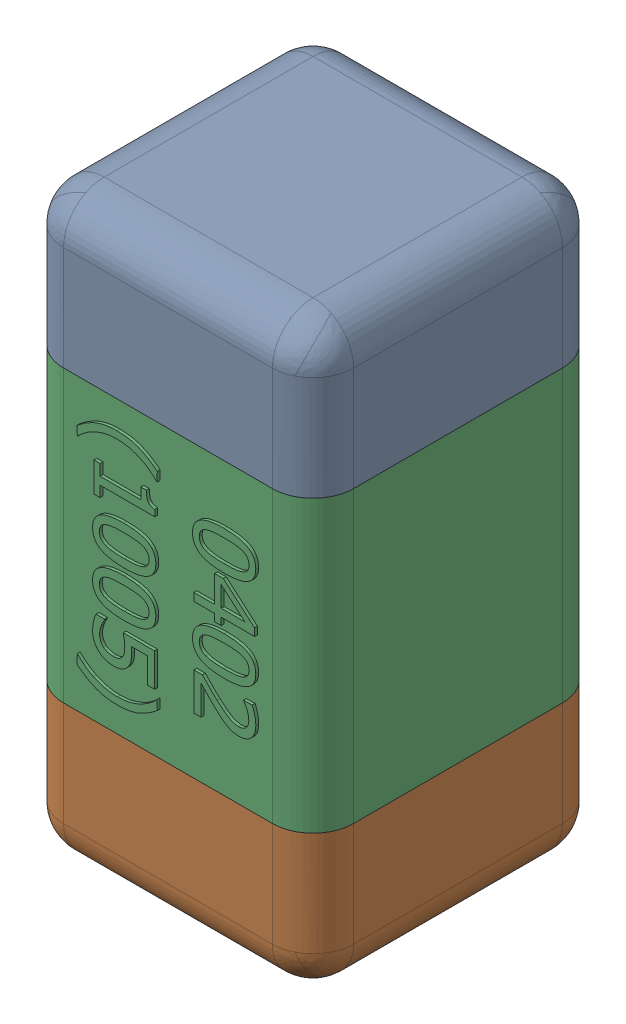
SolidWorks assembly C16, configuration Standard. Lengths in mm.
Overall size (0.51 1.01 0.51).
4 component instances, 3 part files, 0 mates.
Components (placement in the parent):
- C16-subassembly-1-1: C16-subassembly-1 [Standard] at (-2.1 18.0999 0) x (0 -1 0) z (0 0 1) size (1.01 0.51 0.51)
  - User Library-0402_Cap-1: User Library-0402_Cap [Standard] at origin size (0.26 0.51 0.51)
  - User Library-0402_Cap-1-1: User Library-0402_Cap-1 [Standard] at origin size (0.26 0.5 0.51)
  - User Library-0402_Cap-2-1: User Library-0402_Cap-2 [Standard] at origin size (0.5 0.5 0.51)
